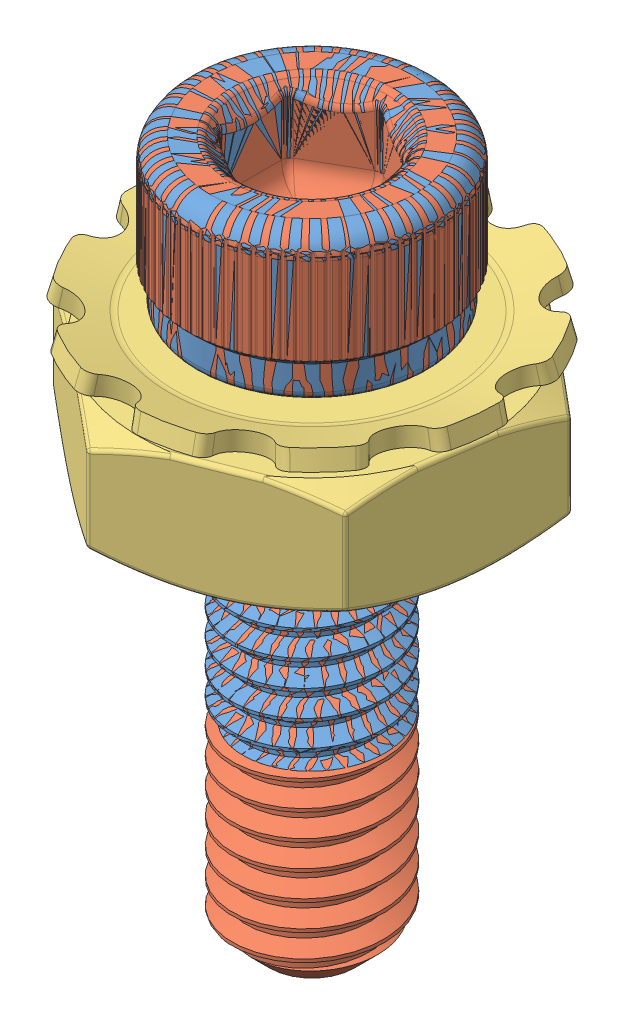
SolidWorks assembly Assem1, configuration Default. Lengths in mm.
Overall size (11.74 16.13 11.52).
3 component instances, 3 part files, 1 mates.
Components (placement in the parent):
- 螺丝M3_3.5 - 8mm-1: 螺丝M3_3.5 - 8mm [Default] at origin size (5.73 12.19 5.73)
- 螺丝M3_3.5-1: 螺丝M3_3.5 [Default] at origin size (5.73 16.13 5.73)
- M3.5 F-1: M3.5 F [默认] at (0 10.7132 0) x (-0.372515 0 -0.928026) z (-0.928026 0 0.372515) size (8.75 3.85 9.13)
Mates (geometry in assembly coordinates):
- Concentric1: concentric aligned: circle of 螺丝M3_3.5 - 8mm-1; circle of M3.5 F-1
